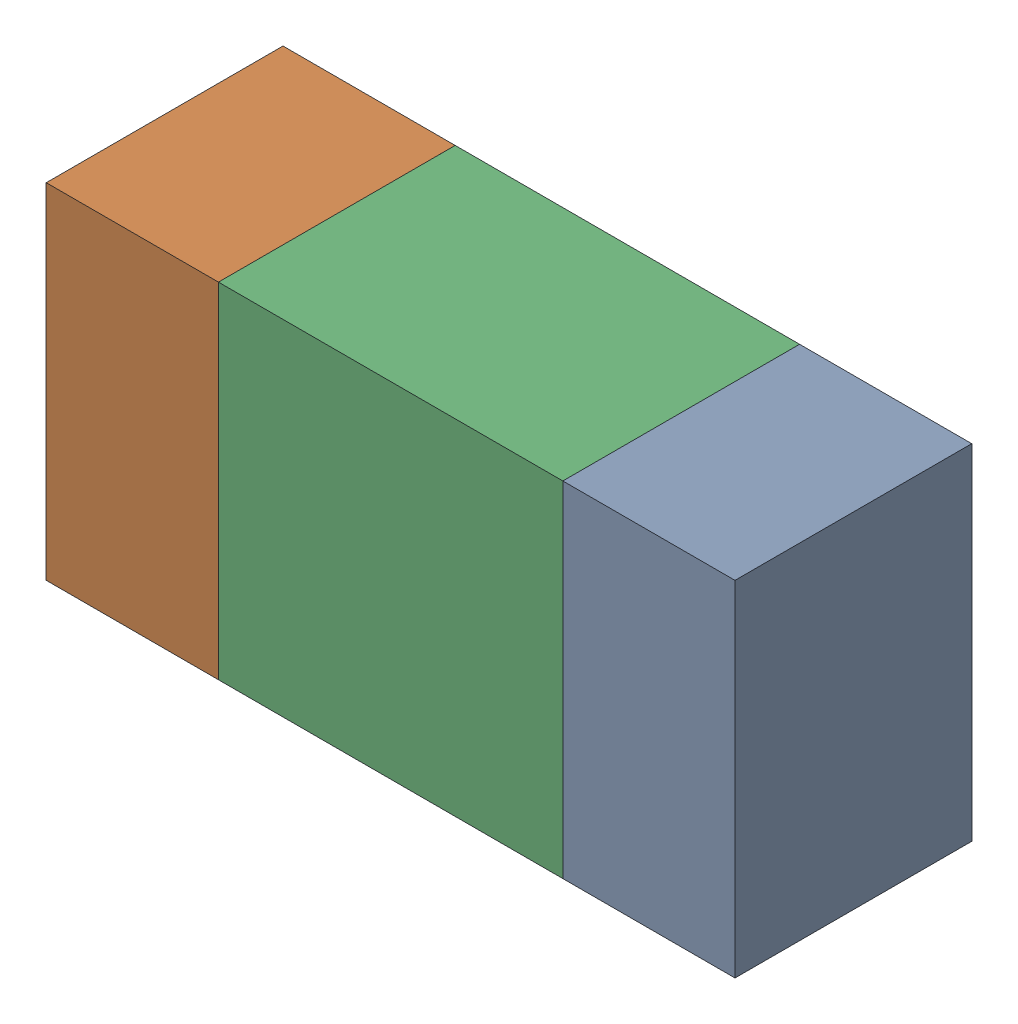
SolidWorks assembly R34, configuration ﾃﾞﾌｫﾙﾄ. Lengths in mm.
Overall size (1.6 0.8 0.55).
6 component instances, 2 part files, 0 mates.
Components (placement in the parent):
- 689261512-1: 689261512 [ﾃﾞﾌｫﾙﾄ] at (11.3949 13.9701 -1.7503) size (0.4 0.8 0.55)
  - Extruded_32-1: Extruded_32 [ﾃﾞﾌｫﾙﾄ] at origin size (0.4 0.8 0.55)
- 689261512-2: 689261512 [ﾃﾞﾌｫﾙﾄ] at (10.1949 13.9701 -1.7503) size (0.4 0.8 0.55)
  - Extruded_32-1: Extruded_32 [ﾃﾞﾌｫﾙﾄ] at origin size (0.4 0.8 0.55)
- 689261648-1: 689261648 [ﾃﾞﾌｫﾙﾄ] at (10.795 13.9701 -1.7503) size (0.8 0.8 0.55)
  - Extruded_33-1: Extruded_33 [ﾃﾞﾌｫﾙﾄ] at origin size (0.8 0.8 0.55)
